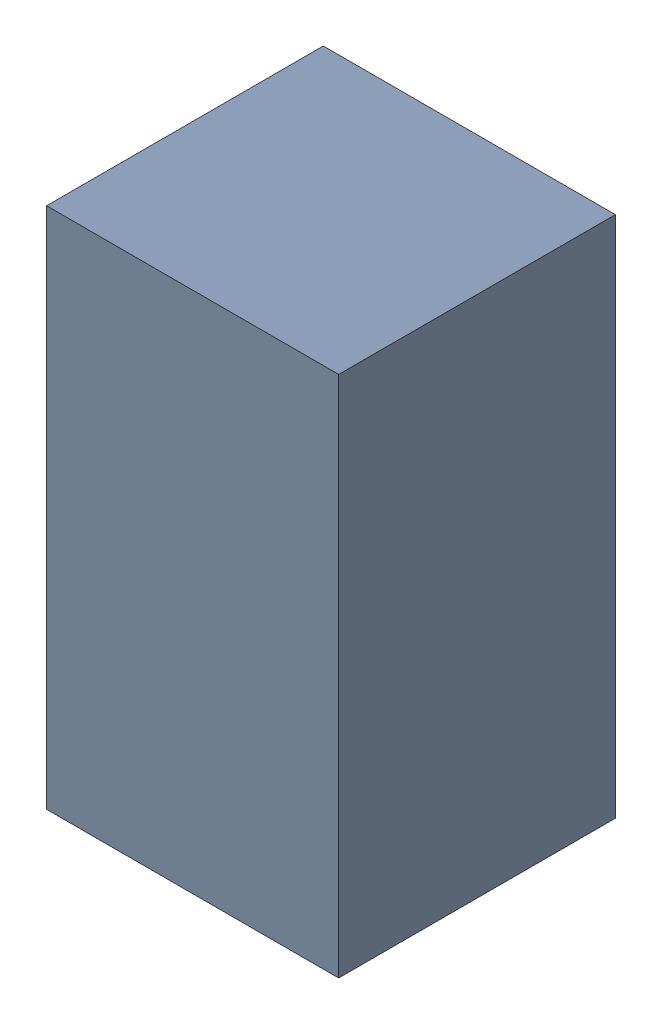
SolidWorks assembly R10, configuration Standard. Lengths in mm.
Overall size (0.95 1.7 0.9).
2 component instances, 1 part files, 0 mates.
Components (placement in the parent):
- 885541560-1: 885541560 [Standard] at (7.95 -0.3 0) size (0.95 1.7 0.9)
  - Extruded_16-1: Extruded_16 [Standard] at origin size (0.95 1.7 0.9)
